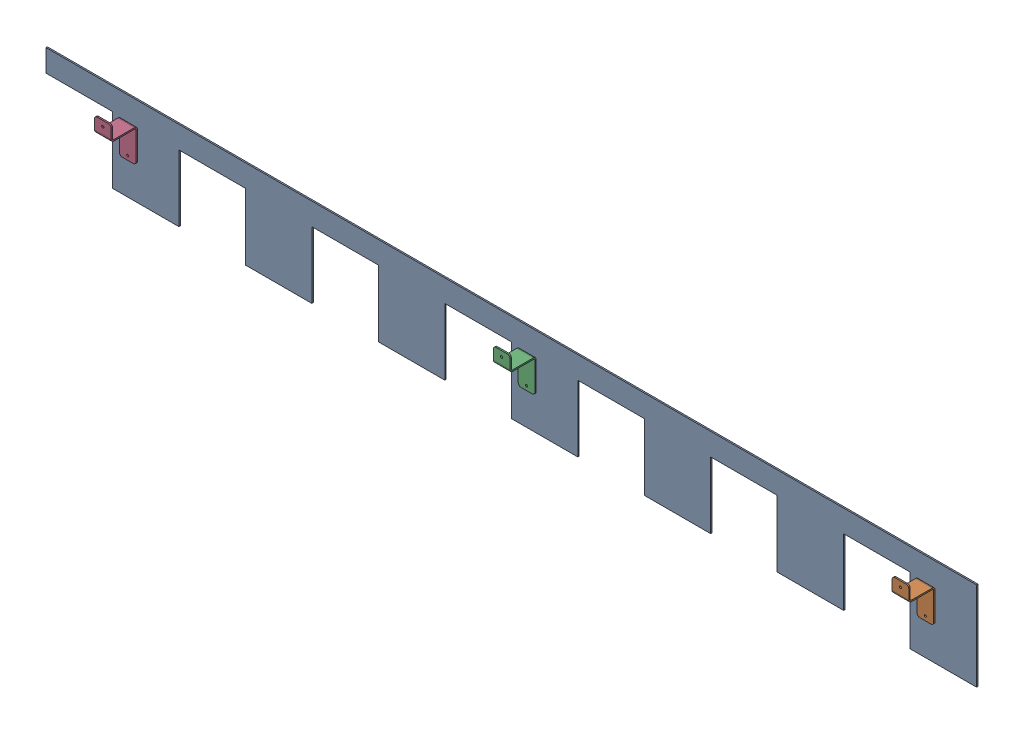
SolidWorks assembly GE-16135_ASM, configuration Default. Lengths in mm.
Overall size (2133.6 203.2 63.5).
4 component instances, 2 part files, 0 mates.
Components (placement in the parent):
- GE-16130-1: GE-16130 [Default] at origin size (2133.6 203.2 3.17)
- GE-16135-1: GE-16135 [Default] at (952.5 50.8 3.175) x (1 0 0) z (0 1 0) size (38.1 60.32 107.95)
- GE-16135-2: GE-16135 [Default] at (38.1 50.8 3.175) x (1 0 0) z (0 1 0) size (38.1 60.32 107.95)
- GE-16135-3: GE-16135 [Default] at (-876.3 50.8 3.175) x (1 0 0) z (0 1 0) size (38.1 60.32 107.95)
